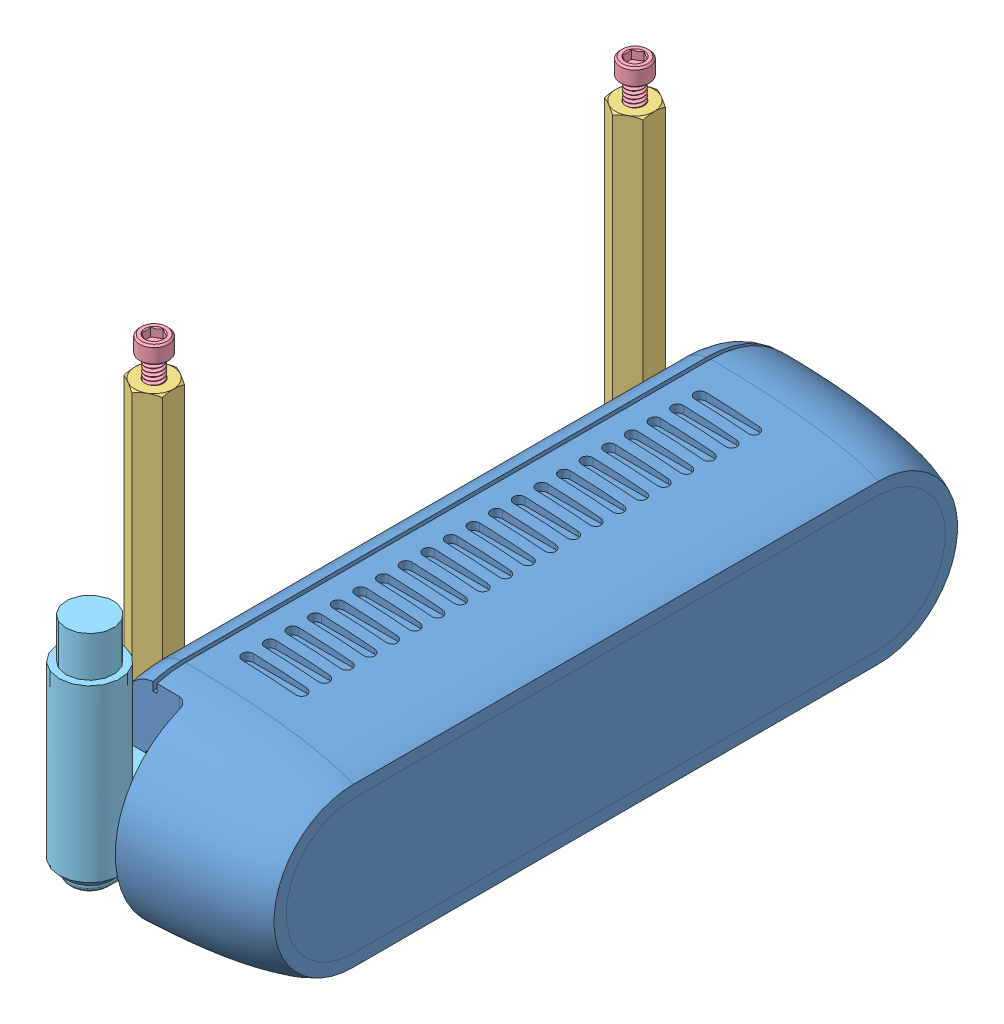
SolidWorks assembly CameraAssembly, configuration Default. Lengths in mm.
Overall size (29.83 60.82 92.75).
9 component instances, 5 part files, 23 mates.
Components (placement in the parent):
- Camera-1: Camera [Default] at (0 12.5 0) size (25.32 25.1 90)
- 97763A262_18-8 Stainless Steel Button Head Hex Drive Screws-1: 97763A262_18-8 Stainless Steel Button Head Hex Drive Screws [97763A262] at (9.6475 1.4861 0) x (-0.837169 0 -0.546944) z (0 -1 0) size (11.1 11.1 13.52)
- 91780A039_Female Threaded Hex Standoff-1: 91780A039_Female Threaded Hex Standoff [91780A039] at (-2.3813 25.4 -29.7504) x (1 0 0) z (0 -1 0) size (4.76 5.5 51.09)
- 91780A039_Female Threaded Hex Standoff-2: 91780A039_Female Threaded Hex Standoff [91780A039] at (-2.3813 25.4 29.7504) x (1 0 0) z (0 -1 0) size (4.76 5.5 51.09)
- 91251A077_Black-Oxide Alloy Steel Socket Head Screw-1: 91251A077_Black-Oxide Alloy Steel Socket Head Screw [91251A077] at (-2.3813 0.4828 -29.7504) x (0.899282 0 -0.437369) z (0 -1 0) size (3.57 3.57 8.83)
- 91251A077_Black-Oxide Alloy Steel Socket Head Screw-2: 91251A077_Black-Oxide Alloy Steel Socket Head Screw [91251A077] at (-2.3813 0.4828 29.7504) x (-0.987174 0 0.159645) z (0 -1 0) size (3.57 3.57 8.83)
- 91251A077_Black-Oxide Alloy Steel Socket Head Screw-3: 91251A077_Black-Oxide Alloy Steel Socket Head Screw [91251A077] at (-2.3813 51.2572 -29.7504) x (-0.513635 0 -0.858009) z (0 1 0) size (3.57 3.57 8.83)
- 91251A077_Black-Oxide Alloy Steel Socket Head Screw-4: 91251A077_Black-Oxide Alloy Steel Socket Head Screw [91251A077] at (-2.3813 51.2572 29.7504) x (-0.513635 0 -0.858009) z (0 1 0) size (3.57 3.57 8.83)
- USBC-1: USBC [Default] at (3.87 35.7 43.975) x (1 0 0) z (0 0 -1) size (7.55 28.1 17.75)
Mates (geometry in assembly coordinates):
- Coincident1: coincident aligned: plane of Camera-1 through (11.25 0 -24.3132) normal (0 -1 0); plane of 91780A039_Female Threaded Hex Standoff-1 through (-2.3813 0 -27.0007) normal (0 -1 0)
- Coincident4: coincident anti-aligned: plane of Camera-1 through (0 12.5 32.5) normal (-1 0 0); plane of 91780A039_Female Threaded Hex Standoff-2 through (0 0 28.3756) normal (1 0 0)
- Coincident7: coincident aligned: plane of Camera-1 through (11.25 0 -24.3132) normal (0 -1 0); plane of 91780A039_Female Threaded Hex Standoff-2 through (-2.3813 0 32.5) normal (0 -1 0)
- Coincident8: coincident aligned: plane of Camera-1 through (11.25 0 -24.3132) normal (0 -1 0); plane of 91780A039_Female Threaded Hex Standoff-1 through (-2.3813 0 -27.0007) normal (0 -1 0)
- Coincident9: coincident anti-aligned: plane of Camera-1 through (0 12.5 32.5) normal (-1 0 0); plane of 91780A039_Female Threaded Hex Standoff-1 through (0 0 -31.1252) normal (1 0 0)
- Coincident10: coincident aligned: plane of Camera-1 through (0 12.5 0) normal (0 0 1)
- Coincident11: coincident aligned: plane of Camera-1 through (0 12.5 0) normal (1 0 0)
- Symmetric1: symmetric aligned: plane of Camera-1 through (0 12.5 0) normal (0 0 1); line of 91780A039_Female Threaded Hex Standoff-1 through (-2.3813 0.2127 -27.0007) axis (0 1 0); line of 91780A039_Female Threaded Hex Standoff-2 through (-2.3813 0.2127 27.0007) axis (0 1 0)
- Coincident12: coincident anti-aligned: plane of Camera-1 through (11.25 0 -24.3132) normal (0 -1 0)
- Concentric1: concentric aligned: circle of Camera-1; cylinder of 97763A262_18-8 Stainless Steel Button Head Hex Drive Screws-1 through (9.6475 -4.9528 0) axis (0 -1 0) radius 5.5499
- Distance1: distance = 1.6 mm anti-aligned: plane of Camera-1 through (11.25 0 -24.3132) normal (0 -1 0); plane of 97763A262_18-8 Stainless Steel Button Head Hex Drive Screws-1 through (12.683 -1.6 -4.6462) normal (0 1 0)
- Concentric2: concentric aligned: circle of 91780A614_Female Threaded Hex Standoff-1; cylinder of 91251A077_Black-Oxide Alloy Steel Socket Head Screw-1 through (-2.3813 4.75 -29.7504) axis (0 1 0) radius 1.7859
- Concentric3: concentric aligned: circle of 91780A614_Female Threaded Hex Standoff-2; cylinder of 91251A077_Black-Oxide Alloy Steel Socket Head Screw-2 through (-2.3813 4.75 29.7504) axis (0 1 0) radius 1.7859
- Coincident13: coincident aligned: plane of 97763A262_18-8 Stainless Steel Button Head Hex Drive Screws-1 through (12.683 -1.6 -4.6462) normal (0 1 0); plane of 91251A077_Black-Oxide Alloy Steel Socket Head Screw-1 through (-1.6957 -1.6 -28.3407) normal (0 1 0)
- Coincident14: coincident aligned: plane of 91251A077_Black-Oxide Alloy Steel Socket Head Screw-1 through (-1.6957 -1.6 -28.3407) normal (0 1 0); plane of 91251A077_Black-Oxide Alloy Steel Socket Head Screw-2 through (-2.6315 -1.6 28.203) normal (0 1 0)
- Coincident18: coincident: line of 91780A039_Female Threaded Hex Standoff-1 through (-2.3813 0.2127 -32.5) axis (0 1 0)
- Concentric4: concentric aligned: circle of 91780A039_Female Threaded Hex Standoff-1; cylinder of 91251A077_Black-Oxide Alloy Steel Socket Head Screw-3 through (-2.3813 46.99 -29.7504) axis (0 -1 0) radius 1.7859
- Distance2: distance = 2.54 mm anti-aligned: plane of 91780A039_Female Threaded Hex Standoff-1 through (-2.3813 50.8 -27.0007) normal (0 1 0); plane of 91251A077_Black-Oxide Alloy Steel Socket Head Screw-3 through (-3.7262 53.34 -28.9452) normal (0 -1 0)
- Concentric5: concentric aligned: circle of 91780A039_Female Threaded Hex Standoff-2; cylinder of 91251A077_Black-Oxide Alloy Steel Socket Head Screw-4 through (-2.3813 46.99 29.7504) axis (0 -1 0) radius 1.7859
- Coincident19: coincident aligned: plane of 91251A077_Black-Oxide Alloy Steel Socket Head Screw-3 through (-2.3813 55.5244 -29.7504) normal (0 1 0); plane of 91251A077_Black-Oxide Alloy Steel Socket Head Screw-4 through (-2.3813 55.5244 29.7504) normal (0 1 0)
- Width1: width aligned: plane of Camera-1 through (5.37 15.425 31) normal (-1 0 0); plane of USBC-1 through (2.37 15.425 31) normal (1 0 0); plane of Camera-1 through (2.68 9.525 30) normal (-1 0 0); plane of USBC-1 through (5.06 9.525 30) normal (1 0 0)
- Distance3: distance = 1 mm anti-aligned: plane of USBC-1 through (3.87 35.7 37) normal (0 0 -1); plane of Camera-1 through (8 0 36) normal (0 0 1)
- Concentric6: concentric aligned: cylinder of Camera-1 through (3.87 15.425 31) axis (0 0 1) radius 1.5; cylinder of USBC-1 through (3.87 15.425 30) axis (0 0 1) radius 1.19
